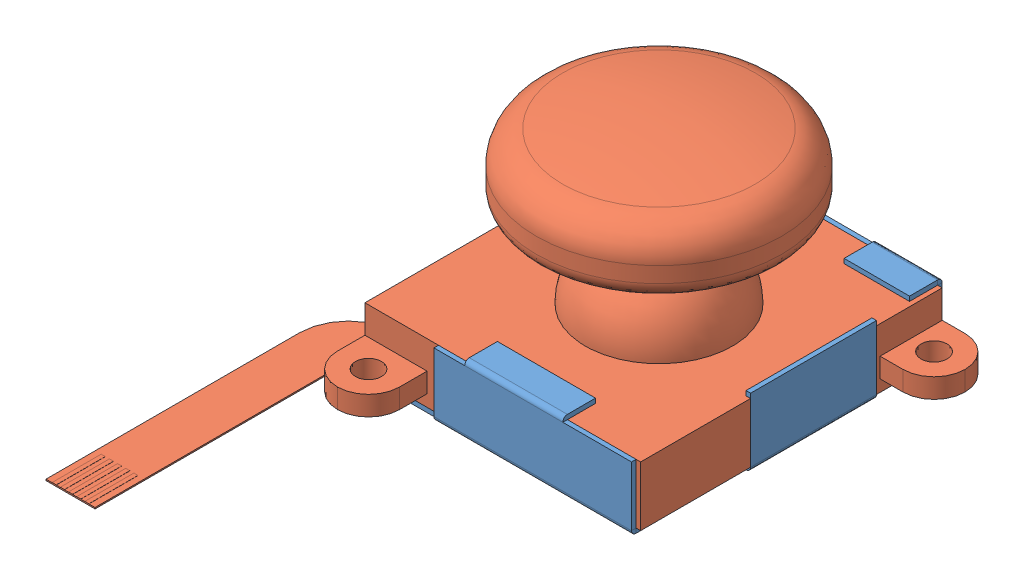
SolidWorks assembly Assem2, configuration Default. Lengths in mm.
Overall size (24.16 14.01 34.22).
2 component instances, 2 part files, 0 mates.
Components (placement in the parent):
- Sheet-1: Sheet [Default] at (7.6951 -14.8045 4.6482) size (17.14 4.43 19)
- Part3^Assem2-1: Part3^Assem2 [Default] at origin size (24.16 13.53 34.22) (virtual)
